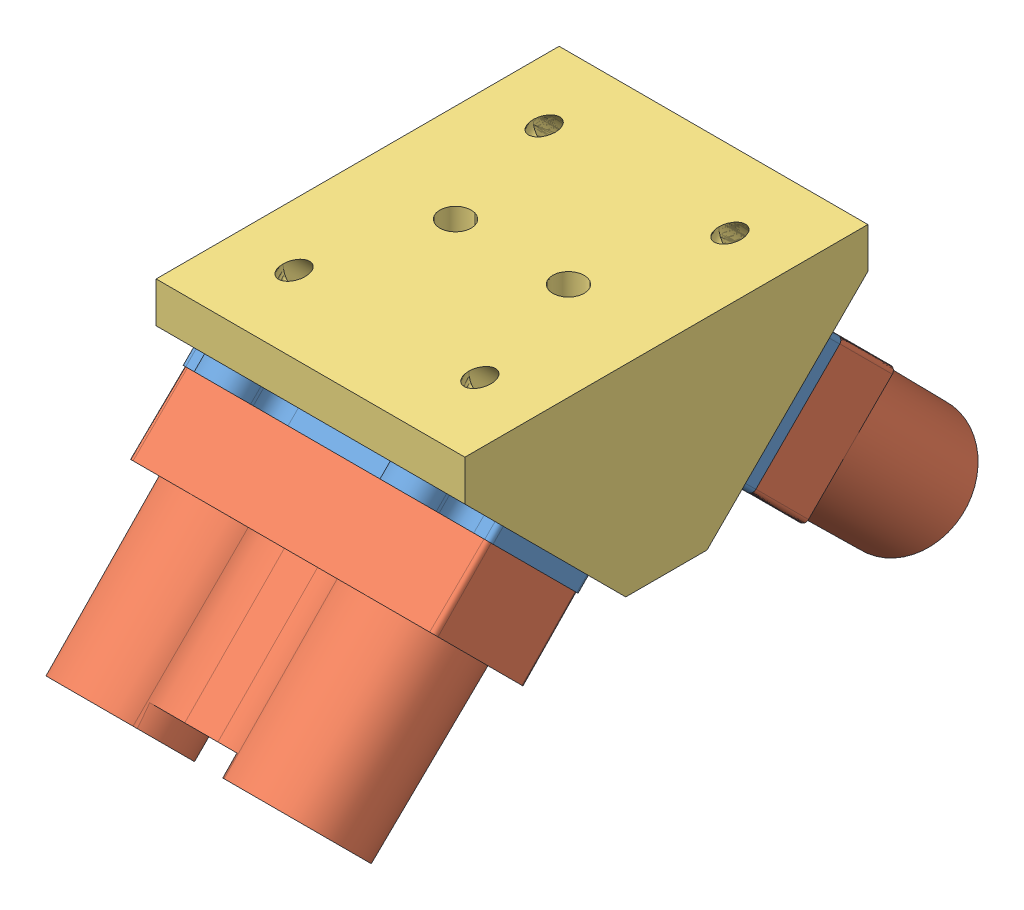
SolidWorks assembly 2_Lidars, configuration Default. Lengths in mm.
Overall size (48.26 59.5 118.99).
7 component instances, 3 part files, 8 mates.
Components (placement in the parent):
- LiDAR_Lite-1: LiDAR_Lite [Default] at (-28.1042 -5.9237 32.1958) x (1 0 0) z (0 0.707107 -0.707107) size (48.26 39.85 35.56)
  - LIDAR-Lite_Base-1: LIDAR-Lite_Base [Default] at (3.9982 4.445 0.3764) x (1 0 0) z (0 -1 0) size (48.26 35.56 5.72)
  - LIDAR-Lite_Housing_RevD-1: LIDAR-Lite_Housing_RevD [Default] at (52.0437 2.54 8.1475) x (-1 0 0) z (0 1 0) size (47.88 20.07 37.31)
- LiDAR_Lite-3: LiDAR_Lite [Default] at (28.1523 -5.9237 44.0042) x (-1 0 0) z (0 0.707107 0.707107) size (48.26 39.85 35.56)
  - LIDAR-Lite_Base-1: LIDAR-Lite_Base [Default] at (3.9982 4.445 0.3764) x (1 0 0) z (0 -1 0) size (48.26 35.56 5.72)
  - LIDAR-Lite_Housing_RevD-1: LIDAR-Lite_Housing_RevD [Default] at (52.0437 2.54 8.1475) x (-1 0 0) z (0 1 0) size (47.88 20.07 37.31)
- 45Block^2_Lidars-1: 45Block^2_Lidars [Default] at (0 25.4 0) x (1 0 0) z (0 1 0) size (48.26 62.99 31.49) (virtual)
Mates (geometry in assembly coordinates):
- Coincident2: coincident anti-aligned: plane of LiDAR_Lite-1; plane of assembly through (0 0 0) normal (1 0 0)
- Coincident5: coincident: line of LiDAR_Lite-1/LIDAR-Lite_Base-1 through (-7.3547 0 26.272) axis (1 0 0); plane of assembly
- Angle2: planar angle = 0.785398 rad aligned: plane of LiDAR_Lite-1/LIDAR-Lite_Base-1 through (-24.106 19.4872 6.7849) normal (0 0.707107 0.707107); plane of assembly through (0 0 0) normal (0 1 0)
- Distance1: distance = 6.35 mm: plane of assembly through (0 0 38.1) normal (0 0 1); moEndPointRef_w of LiDAR_Lite-1/LIDAR-Lite_Base-1
- InPlace1: in place: plane of 45Block^2_Lidars-1 through (0 25.4 0) normal (0 1 0); moOrthogonalPlaneRef_w of 45Block^2_Lidars-1 through (0 25.4 0) normal (0 0 -1); line of 45Block^2_Lidars-1 through (-55 0 25.4) axis (0 1 0); unknown of 45Block^2_Lidars-1
- Coincident9: coincident aligned: plane of 45Block^2_Lidars-1; plane of assembly
- Coincident10: coincident aligned: plane of 45Block^2_Lidars-1 through (0 25.4 0) normal (0 0 -1); moOrthogonalPlaneRef_w of assembly
- Coincident11: coincident anti-aligned: plane of 45Block^2_Lidars-1; moOrthogonalPlaneRef_w of assembly
